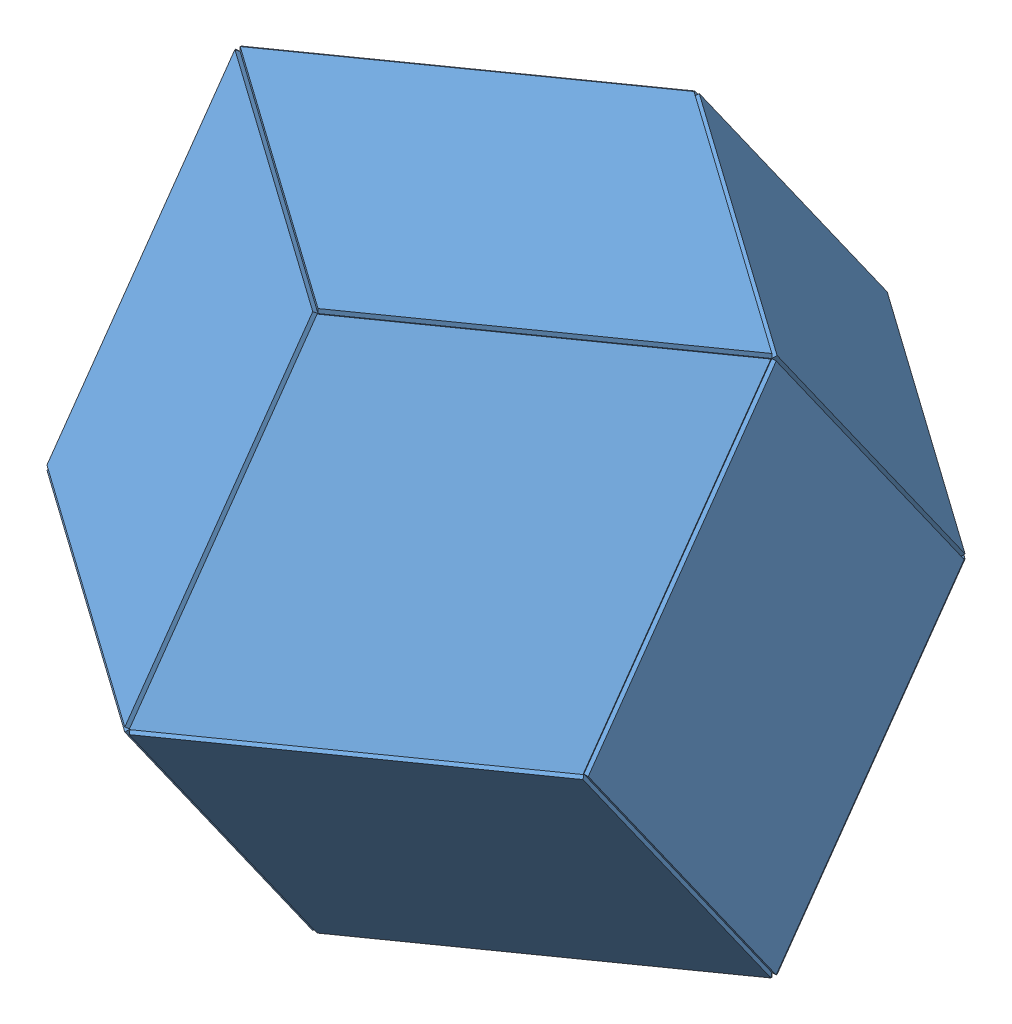
SolidWorks assembly Assem1, configuration Default. Lengths in mm.
Overall size (459.7 459.7 434.59).
12 component instances, 1 part files, 22 mates.
Components (placement in the parent):
- Rhombic Dodeca Face-1: Rhombic Dodeca Face [Default] at origin size (304.8 2.5 215.53)
- Rhombic Dodeca Face-2: Rhombic Dodeca Face [Default] at (-76.825 76.825 -108.647) x (-0.5 -0.5 0.707107) z (-0.707107 0.707107 0) size (304.8 2.5 215.53)
- Rhombic Dodeca Face-3: Rhombic Dodeca Face [Default] at (76.825 76.825 -108.647) x (0.5 -0.5 0.707107) z (-0.707107 -0.707107 0) size (304.8 2.5 215.53)
- Rhombic Dodeca Face-4: Rhombic Dodeca Face [Default] at (76.825 76.825 108.647) x (-0.5 0.5 0.707107) z (-0.707107 -0.707107 0) size (304.8 2.5 215.53)
- Rhombic Dodeca Face-5: Rhombic Dodeca Face [Default] at (-76.825 76.825 108.647) x (-0.5 -0.5 -0.707107) z (0.707107 -0.707107 0) size (304.8 2.5 215.53)
- Rhombic Dodeca Face-6: Rhombic Dodeca Face [Default] at (-76.825 230.475 -108.647) x (0.5 -0.5 -0.707107) z (0.707107 0.707107 0) size (304.8 2.5 215.53)
- Rhombic Dodeca Face-7: Rhombic Dodeca Face [Default] at (76.825 230.475 -108.647) x (0.5 0.5 0.707107) z (-0.707107 0.707107 0) size (304.8 2.5 215.53)
- Rhombic Dodeca Face-8: Rhombic Dodeca Face [Default] at (76.825 230.475 108.647) x (-0.5 -0.5 0.707107) z (-0.707107 0.707107 0) size (304.8 2.5 215.53)
- Rhombic Dodeca Face-9: Rhombic Dodeca Face [Default] at (-76.825 230.475 108.647) x (0.5 -0.5 0.707107) z (-0.707107 -0.707107 0) size (304.8 2.5 215.53)
- Rhombic Dodeca Face-10: Rhombic Dodeca Face [Default] at (153.65 153.65 0) x (0 -1 0) z (0 0 1) size (304.8 2.5 215.53)
- Rhombic Dodeca Face-11: Rhombic Dodeca Face [Default] at (-153.65 153.65 0) x (0 1 0) z (0 0 1) size (304.8 2.5 215.53)
- Rhombic Dodeca Face-12: Rhombic Dodeca Face [Default] at (0 307.3 0) size (304.8 2.5 215.53)
Mates (geometry in assembly coordinates):
- Coincident1: coincident anti-aligned: line of Rhombic Dodeca Face-1 through (-152.4 1.25 0) axis (0.816497 0 0.57735); line of Rhombic Dodeca Face-5 through (0 1.25 107.7631) axis (-0.816497 0 -0.57735)
- Coincident2: coincident: point of Rhombic Dodeca Face-1; point of Rhombic Dodeca Face-5
- Coincident3: coincident anti-aligned: line of Rhombic Dodeca Face-1 through (0 1.25 107.7631) axis (0.816497 0 -0.57735); line of Rhombic Dodeca Face-4 through (152.4 1.25 0) axis (-0.816497 0 0.57735)
- Coincident4: coincident anti-aligned: line of Rhombic Dodeca Face-4 through (0 1.25 107.7631) axis (0 0.816497 0.57735); line of Rhombic Dodeca Face-5 through (0 153.65 215.5261) axis (0 -0.816497 -0.57735)
- Coincident5: coincident anti-aligned: line of Rhombic Dodeca Face-1 through (0 1.25 -107.7631) axis (-0.816497 0 0.57735); line of Rhombic Dodeca Face-2 through (-152.4 1.25 0) axis (0.816497 0 -0.57735)
- Coincident6: coincident: point of Rhombic Dodeca Face-1; point of Rhombic Dodeca Face-2
- Coincident7: coincident anti-aligned: line of Rhombic Dodeca Face-2 through (0 1.25 -107.7631) axis (0 0.816497 -0.57735); line of Rhombic Dodeca Face-3 through (0 153.65 -215.5261) axis (0 -0.816497 0.57735)
- Coincident8: coincident anti-aligned: line of Rhombic Dodeca Face-1 through (152.4 1.25 0) axis (-0.816497 0 -0.57735); line of Rhombic Dodeca Face-3 through (0 1.25 -107.7631) axis (0.816497 0 0.57735)
- Coincident9: coincident aligned: line of Rhombic Dodeca Face-5 through (-152.4 1.25 0) axis (0 0.816497 0.57735); line of Rhombic Dodeca Face-11 through (-152.4 1.25 0) axis (0 0.816497 0.57735)
- Coincident10: coincident aligned: line of Rhombic Dodeca Face-2 through (-152.4 153.65 -107.7631) axis (0 -0.816497 0.57735); line of Rhombic Dodeca Face-11 through (-152.4 153.65 -107.7631) axis (0 -0.816497 0.57735)
- Coincident12: coincident: line of Rhombic Dodeca Face-2 through (0 153.65 -215.5261) axis (-0.816497 0 0.57735); line of Rhombic Dodeca Face-6 through (0 153.65 -215.5261) axis (-0.816497 0 0.57735)
- Coincident13: coincident anti-aligned: line of Rhombic Dodeca Face-6 through (-152.4 153.65 -107.7631) axis (0 0.816497 0.57735); line of Rhombic Dodeca Face-11 through (-152.4 306.05 0) axis (0 -0.816497 -0.57735)
- Coincident14: coincident aligned: line of Rhombic Dodeca Face-4 through (152.4 153.65 107.7631) axis (0 -0.816497 -0.57735); line of Rhombic Dodeca Face-10 through (152.4 153.65 107.7631) axis (0 -0.816497 -0.57735)
- Coincident15: coincident aligned: line of Rhombic Dodeca Face-3 through (152.4 1.25 0) axis (0 0.816497 -0.57735); line of Rhombic Dodeca Face-10 through (152.4 1.25 0) axis (0 0.816497 -0.57735)
- Coincident16: coincident anti-aligned: line of Rhombic Dodeca Face-7 through (152.4 306.05 0) axis (0 -0.816497 -0.57735); line of Rhombic Dodeca Face-10 through (152.4 153.65 -107.7631) axis (0 0.816497 0.57735)
- Coincident17: coincident aligned: line of Rhombic Dodeca Face-3 through (152.4 153.65 -107.7631) axis (-0.816497 0 -0.57735); line of Rhombic Dodeca Face-7 through (152.4 153.65 -107.7631) axis (-0.816497 0 -0.57735)
- Coincident18: coincident aligned: line of Rhombic Dodeca Face-5 through (-152.4 153.65 107.7631) axis (0.816497 0 0.57735); line of Rhombic Dodeca Face-9 through (-152.4 153.65 107.7631) axis (0.816497 0 0.57735)
- Coincident19: coincident anti-aligned: line of Rhombic Dodeca Face-9 through (-152.4 306.05 0) axis (0 -0.816497 0.57735); line of Rhombic Dodeca Face-11 through (-152.4 153.65 107.7631) axis (0 0.816497 -0.57735)
- Coincident20: coincident anti-aligned: line of Rhombic Dodeca Face-8 through (152.4 153.65 107.7631) axis (0 0.816497 -0.57735); line of Rhombic Dodeca Face-10 through (152.4 306.05 0) axis (0 -0.816497 0.57735)
- Coincident21: coincident aligned: line of Rhombic Dodeca Face-4 through (0 153.65 215.5261) axis (0.816497 0 -0.57735); line of Rhombic Dodeca Face-8 through (0 153.65 215.5261) axis (0.816497 0 -0.57735)
- Coincident22: coincident anti-aligned: line of Rhombic Dodeca Face-7 through (0 306.05 -107.7631) axis (0.816497 0 0.57735); line of Rhombic Dodeca Face-12 through (152.4 306.05 0) axis (-0.816497 0 -0.57735)
- Coincident23: coincident anti-aligned: line of Rhombic Dodeca Face-6 through (-152.4 306.05 0) axis (0.816497 0 -0.57735); line of Rhombic Dodeca Face-12 through (0 306.05 -107.7631) axis (-0.816497 0 0.57735)
